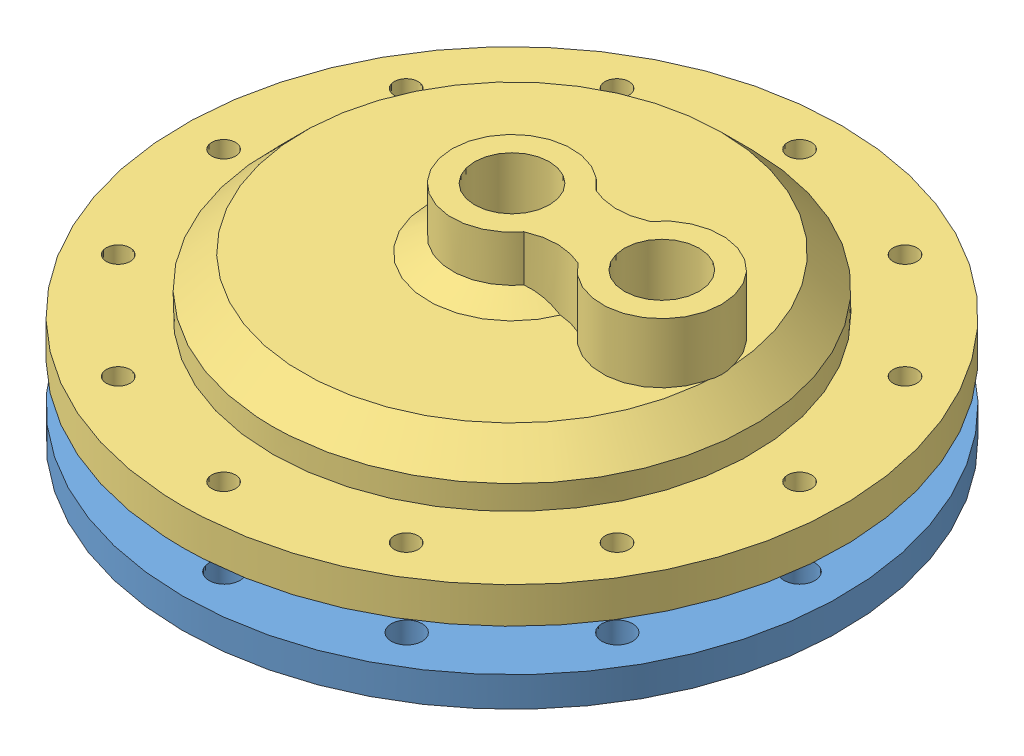
SolidWorks assembly Injector Assembly V6-6-4_11-64, configuration Default. Lengths in mm.
Overall size (139.7 47.17 139.7).
3 component instances, 3 part files, 10 mates.
Components (placement in the parent):
- Injector V4-1: Injector V4 [Default] x (1 0 0) z (0 0 -1) size (139.7 6.35 139.7)
- Distribution Plate V4-1: Distribution Plate V4 [Default] at origin size (79.66 15.24 79.66)
- Top Plate V4-1: Top Plate V4 [Default] at (0 8.89 0) size (139.7 31.93 139.7)
Mates (geometry in assembly coordinates):
- Coincident1: coincident aligned: plane of Injector V4-1 through (0 0 0) normal (0 1 0)
- Coincident2: coincident anti-aligned: plane of Injector V4-1 through (0 0 0) normal (0 0 -1)
- Coincident3: coincident aligned: plane of Injector V4-1 through (0 0 0) normal (1 0 0)
- Coincident4: coincident anti-aligned: plane of Injector V4-1 through (0 -6.35 0) normal (0 -1 0); plane of FLANGE-1 through (0 -6.35 0) normal (0 1 0)
- Concentric1: concentric anti-aligned: cylinder of Injector V4-1 through (0 -6.35 0) axis (0 1 0) radius 69.85; cylinder of FLANGE-1 through (0 -26.67 0) axis (0 -1 0) radius 73.025
- Concentric2: concentric aligned: cylinder of Injector V4-1 through (30.48 -6.35 -52.7929) axis (0 1 0) radius 3.2639; cylinder of FLANGE-1 through (30.48 -25.4 -52.7929) axis (0 1 0) radius 2.4892
- Concentric3: concentric aligned: cylinder of FLANGE-1 through (0 -26.67 0) axis (0 -1 0) radius 73.025; cylinder of Distribution Plate V4-1 through (0 8.89 0) axis (0 -1 0) radius 69.85
- Coincident5: coincident: plane of Injector V4-1 through (0 0 0) normal (0 1 0); plane of Distribution Plate V4-1 through (0 0 0) normal (0 -1 0)
- Concentric4: concentric: cylinder of Distribution Plate V4-1 through (0 8.89 0) axis (0 -1 0) radius 69.85; cylinder of Top Plate V4-1 through (0 21.59 0) axis (0 -1 0) radius 69.85
- Coincident6: coincident anti-aligned: plane of Distribution Plate V4-1 through (0 8.89 0) normal (0 1 0); plane of Top Plate V4-1 through (0 8.89 0) normal (0 -1 0)
